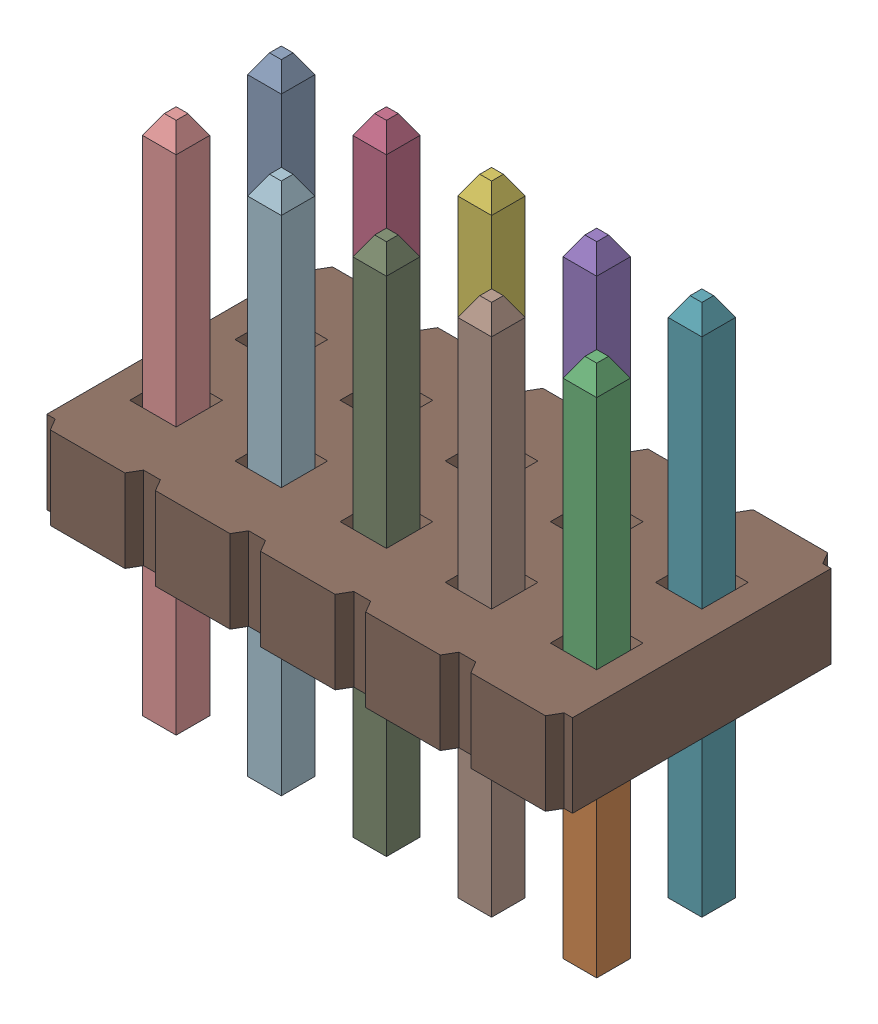
SolidWorks assembly C-L10_FTS-105-02-X-DV-SA_ANY_ASM, configuration Default. Lengths in mm.
Overall size (6.35 6.3 3.41).
11 component instances, 3 part files, 0 mates.
Components (placement in the parent):
- T-1S15_-02_FTSH-DV_ANY-1: T-1S15_-02_FTSH-DV_ANY [Default] at (-2.54 -0.635 -0.635) x (0 0 -1) z (1 0 0) size (0.41 6.3 0.41)
- T-1S15_-02_FTSH-DV_ANY_AF0-1: T-1S15_-02_FTSH-DV_ANY_AF0 [Default] at (2.54 -0.635 0.635) x (0 0 1) z (-1 0 0) size (0.41 6.3 0.41)
- T-1S15_-02_FTSH-DV_ANY-2: T-1S15_-02_FTSH-DV_ANY [Default] at (-1.27 -0.635 -0.635) x (0 0 -1) z (1 0 0) size (0.41 6.3 0.41)
- T-1S15_-02_FTSH-DV_ANY-3: T-1S15_-02_FTSH-DV_ANY [Default] at (1.27 -0.635 -0.635) x (0 0 -1) z (1 0 0) size (0.41 6.3 0.41)
- T-1S15_-02_FTSH-DV_ANY-4: T-1S15_-02_FTSH-DV_ANY [Default] at (0 -0.635 -0.635) x (0 0 -1) z (1 0 0) size (0.41 6.3 0.41)
- T-1S15_-02_FTSH-DV_ANY-5: T-1S15_-02_FTSH-DV_ANY [Default] at (2.54 -0.635 -0.635) x (0 0 -1) z (1 0 0) size (0.41 6.3 0.41)
- T-1S15_-02_FTSH-DV_ANY-6: T-1S15_-02_FTSH-DV_ANY [Default] at (1.27 -0.635 0.635) x (0 0 1) z (-1 0 0) size (0.41 6.3 0.41)
- T-1S15_-02_FTSH-DV_ANY-7: T-1S15_-02_FTSH-DV_ANY [Default] at (0 -0.635 0.635) x (0 0 1) z (-1 0 0) size (0.41 6.3 0.41)
- T-1S15_-02_FTSH-DV_ANY-8: T-1S15_-02_FTSH-DV_ANY [Default] at (-2.54 -0.635 0.635) x (0 0 1) z (-1 0 0) size (0.41 6.3 0.41)
- FTS-X-DV_FORMULA_ANY_AF0-1: FTS-X-DV_FORMULA_ANY_AF0 [Default] at origin size (6.35 1 3.41)
- T-1S15_-02_FTSH-DV_ANY-9: T-1S15_-02_FTSH-DV_ANY [Default] at (-1.27 -0.635 0.635) x (0 0 1) z (-1 0 0) size (0.41 6.3 0.41)
